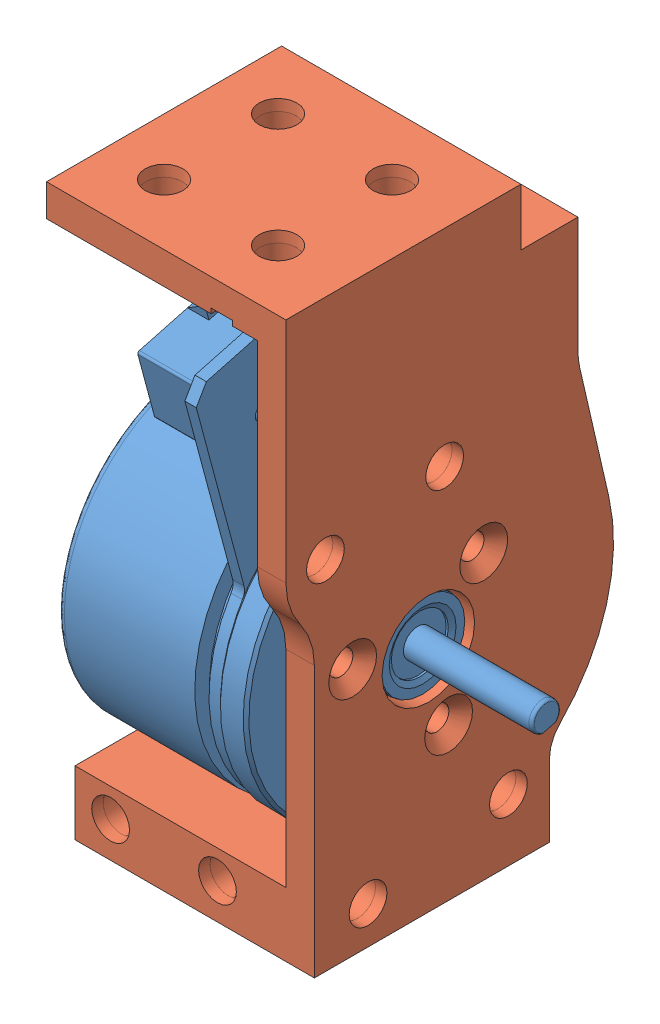
SolidWorks assembly motor angled, configuration Default. Lengths in mm.
Overall size (50.24 82 58.89).
2 component instances, 2 part files, 3 mates.
Components (placement in the parent):
- MaxonMotor-1: MaxonMotor [Default] at (14.4735 35.8888 51.2761) x (-1 0 0) z (0 -0.258819 0.965926) size (47.54 66.3 43.2)
- Front Drivemount_R-1: Front Drivemount_R [AngleUp] at (-15.1265 35.8888 51.2761) size (33.6 82 46)
Mates (geometry in assembly coordinates):
- Coincident4: coincident anti-aligned: plane of MaxonMotor-1 through (14.4735 35.8888 51.2761) normal (1 0 0); plane of Front Drivemount_R-1 through (14.4735 35.8888 51.2761) normal (-1 0 0)
- Concentric3: concentric anti-aligned: cylinder of MaxonMotor-1 through (14.4735 35.8888 51.2761) axis (-1 0 0) radius 6; cylinder of Front Drivemount_R-1 through (-15.1265 35.8888 51.2761) axis (1 0 0) radius 6.5
- Concentric4: concentric anti-aligned: cylinder of MaxonMotor-1 through (14.4735 38.7358 61.9013) axis (1 0 0) radius 1.25; cone of Front Drivemount_R-1 through (18.4735 38.7358 61.9013) axis (-1 0 0)
